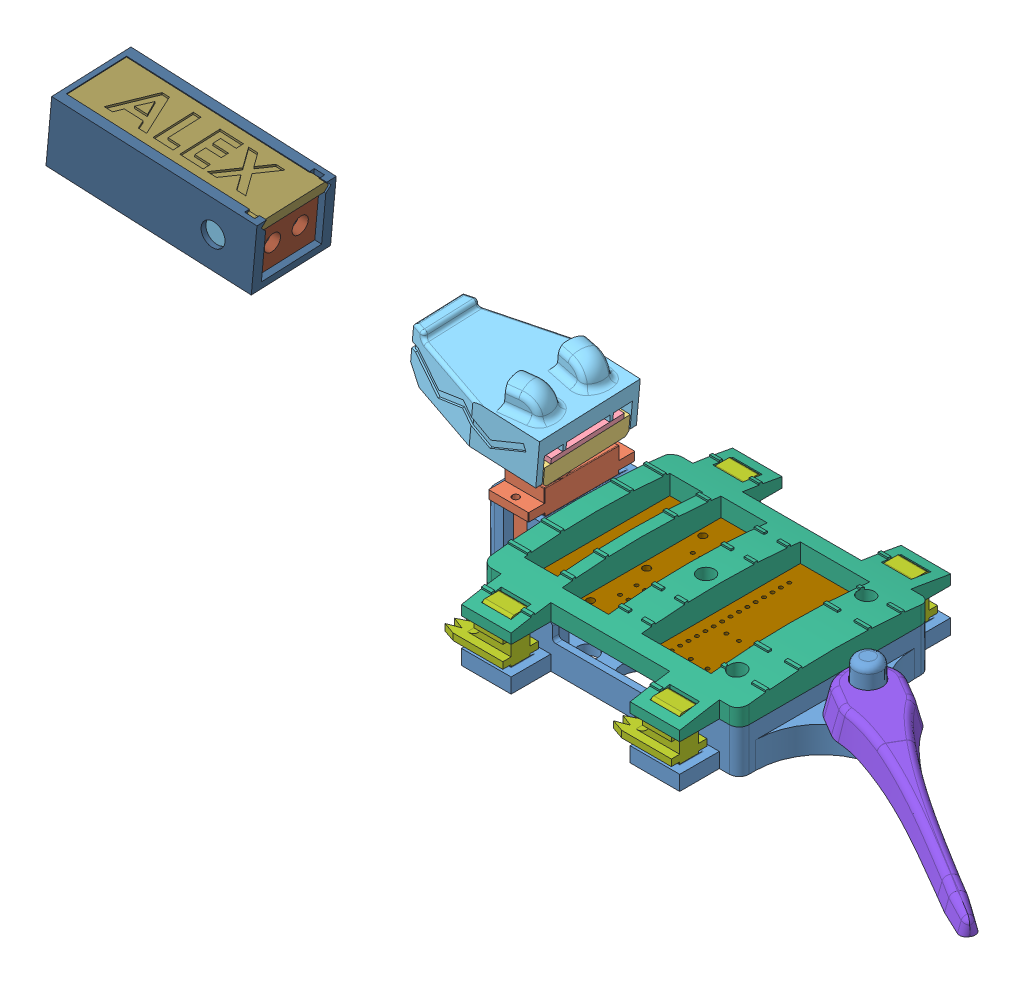
SolidWorks assembly Full Assem, configuration Default. Lengths in mm.
Overall size (309.58 66.54 94.12).
20 component instances, 14 part files, 33 mates.
Components (placement in the parent):
- Base-1: Base [Default] at origin size (113.5 23 82)
- SG90 SERVO-1: SG90 SERVO [Default] at (-49.45 1.1 -5.775) x (-1 0 0) z (0 1 0) size (12.35 32.2 30.15)
- GatorHead Assem-1: GatorHead Assem [Default] at (-51.3952 31.4702 -0.4724) x (0.039866 0 0.999205) z (-0.995403 0.087156 0.039714) size (31.75 20.5 44.45)
  - ServoHead-1: ServoHead [Default] at origin size (27 5.5 37.18)
  - SampleCircuitBoard-1: SampleCircuitBoard [Default] at (0 5.5 -3) size (23 1.5 22)
  - GatorHead-1: GatorHead [Default] at (0 1.3 8.225) size (31.75 19.2 44.45)
- GatorBody V2-1: GatorBody V2 [Default] at (0 13 0) size (78 7.26 82)
- GatorLegs-1: GatorLegs [Default] at (-21.25 8.75 34.875) x (0 1 0) z (0 0 1) size (16.5 18.75 10.75)
- GatorTail-1: GatorTail [Default] at (42.9693 9 -3.554) x (0.861525 0 0.507716) z (-0.507716 0 0.861525) size (94 9.48 21.08)
- GatorLegs-2: GatorLegs [Default] at (-21.25 8.75 -34.875) x (0 1 0) z (0 0 1) size (16.5 18.75 10.75)
- GatorLegs-3: GatorLegs [Default] at (29.75 8.75 34.875) x (0 1 0) z (0 0 1) size (16.5 18.75 10.75)
- GatorLegs-4: GatorLegs [Default] at (29.75 8.75 -34.875) x (0 1 0) z (0 0 1) size (16.5 18.75 10.75)
- SampleShield V2-1: SampleShield V2 [Default] at (0 11 0) size (70 1.5 50)
- FlashlightAssem-1: FlashlightAssem [Default] at (-149.8443 45 6.8332) x (0.995403 -0.087156 -0.039714) z (0.039866 0 0.999205) size (60 19 25)
  - FlashlightBase-1: FlashlightBase [Default] at origin size (60 19 25)
  - LEDInsert-1: LEDInsert [Default] at (25.25 8.875 0.125) x (0 -1 0) z (0 0 1) size (13.75 2.75 21.75)
  - FlashlightTop V2-1: FlashlightTop V2 [Default] at (0.5 16 0) size (58 2.75 21.75)
  - FlashlightConeInsert-1: FlashlightConeInsert [Default] at (-15 11 -6.875) x (-0.874067 0 -0.485806) z (-0.485806 0 0.874067) size (8 7.5 8) (hidden)
  - FlashlightConeInsert-2: FlashlightConeInsert [Default] at (0 11 4.875) x (-0.834603 0 -0.550852) z (-0.550852 0 0.834603) size (8 7.5 8)
  - SampleFlashlightPCB-1: SampleFlashlightPCB [Default] at (0.25 2 0) size (50 1.5 18)
Mates (geometry in assembly coordinates):
- Coincident1: coordinate: point of Base-1
- Coincident2: coincident anti-aligned: plane of Base-1 through (0 3 0) normal (0 1 0); plane of BreadBoard-1 through (-4.15 3 0) normal (0 -1 0)
- Coincident3: coincident anti-aligned: plane of Base-1 through (37 120.2008 0) normal (-1 0 0); plane of BreadBoard-1 through (37 11 -27) normal (1 0 0)
- Coincident4: coincident anti-aligned: plane of Base-1 through (0 120.2008 -27) normal (0 0 1); plane of BreadBoard-1 through (-45.3 11 -27) normal (0 0 -1)
- Concentric1: concentric anti-aligned: cylinder of SG90 SERVO-1 through (-49.45 29.6 -0.55) axis (0 1 0) radius 2.45; cylinder of GatorHead Assem-1/ServoHead-1 through (-49.45 34.25 -0.55) axis (0 -1 0) radius 3
- Coincident15: coincident aligned: plane of Base-1 through (0 0 0) normal (0 0 1); plane of GatorBody V2-1 through (0 13 0) normal (0 0 1)
- Coincident16: coincident aligned: plane of Base-1 through (0 0 0) normal (1 0 0); plane of GatorBody V2-1 through (0 13 0) normal (1 0 0)
- Coincident17: coincident anti-aligned: plane of Base-1 through (-30 4.5 0) normal (1 0 0); plane of GatorLegs-1 through (-30 8.75 34.875) normal (-1 0 0)
- Coincident18: coincident anti-aligned: plane of Base-1 through (0 4.5 32) normal (0 0 1); plane of GatorLegs-1 through (-30 8.75 32) normal (0 0 -1)
- Concentric2: concentric aligned: cylinder of Base-1 through (49 44.3137 0) axis (0 -1 0) radius 4; cylinder of GatorTail-1 through (49 69 0) axis (0 -1 0) radius 4.25
- Coincident22: coincident anti-aligned: plane of Base-1 through (21 4.5 0) normal (1 0 0); plane of GatorLegs-3 through (21 8.75 34.875) normal (-1 0 0)
- Coincident24: coincident anti-aligned: plane of Base-1 through (0 4.5 32) normal (0 0 1); plane of GatorLegs-3 through (21 8.75 32) normal (0 0 -1)
- Coincident26: coincident anti-aligned: plane of Base-1 through (0 4.5 -32) normal (0 0 -1); plane of GatorLegs-2 through (-30 8.75 -32) normal (0 0 1)
- Coincident27: coincident aligned: plane of GatorLegs-2 through (-30 8.75 -37.75) normal (0 0 -1); plane of GatorLegs-4 through (21 8.75 -37.75) normal (0 0 -1)
- Coincident28: coincident anti-aligned: plane of Base-1 through (-30 4.5 0) normal (1 0 0); plane of GatorLegs-2 through (-30 8.75 -34.875) normal (-1 0 0)
- Coincident29: coincident anti-aligned: plane of Base-1 through (21 4.5 0) normal (1 0 0); plane of GatorLegs-4 through (21 8.75 -34.875) normal (-1 0 0)
- Coincident31: coincident aligned: plane of GatorLegs-2 through (-30 17 -34.875) normal (0 1 0); plane of GatorLegs-4 through (21 17 -34.875) normal (0 1 0)
- Coincident32: coincident anti-aligned: plane of Base-1 through (0 17 0) normal (0 1 0); plane of SG90 SERVO-1 through (-49.45 17 -5.775) normal (0 -1 0)
- Coincident34: coincident anti-aligned: plane of Base-1 through (49 9 0) normal (0 1 0); plane of GatorTail-1 through (56.7537 9 4.5694) normal (0 -1 0)
- Distance1: distance = 3 mm anti-aligned: plane of SG90 SERVO-1 through (-49.45 31.25 -5.775) normal (0 1 0); plane of GatorHead Assem-1/ServoHead-1 through (-51.3952 34.25 -0.4724) normal (0 -1 0)
- Coincident36: coincident anti-aligned: plane of Base-1 through (0 4.5 0) normal (0 1 0); plane of GatorLegs-1 through (-30 4.5 34.875) normal (0 -1 0)
- Coincident37: coincident aligned: plane of GatorLegs-3 through (21 17 34.875) normal (0 1 0); plane of GatorLegs-4 through (21 17 -34.875) normal (0 1 0)
- Coincident38: coincident aligned: plane of GatorLegs-1 through (-30 17 34.875) normal (0 1 0); plane of GatorLegs-3 through (21 17 34.875) normal (0 1 0)
- Coincident39: coincident anti-aligned: plane of Base-1 through (0 66.9464 5.5) normal (0 0 -1); plane of SG90 SERVO-1 through (-43.4 1.1 5.5) normal (0 0 1)
- Coincident40: coincident anti-aligned: plane of Base-1 through (-55.5 66.9464 0) normal (1 0 0); plane of SG90 SERVO-1 through (-55.5 1.1 5.5) normal (-1 0 0)
- Coincident42: coincident aligned: plane of Base-1 through (0 0 0) normal (0 0 1); plane of SampleShield V2-1 through (0 11 0) normal (0 0 1)
- Coincident43: coincident aligned: plane of Base-1 through (0 0 0) normal (1 0 0); plane of SampleShield V2-1 through (0 11 0) normal (1 0 0)
- Coincident44: coincident anti-aligned: plane of GatorBody V2-1 through (0 13 0) normal (0 -1 0); plane of GatorLegs-1 through (-30 13 34.875) normal (0 1 0)
- Coincident45: coincident: unknown of FlashlightAssem-1
- Parallel1: parallel anti-aligned: plane of GatorHead Assem-1/GatorHead-1 through (-81.1188 48.0708 -15.1741) normal (-0.995403 0.087156 0.039714); plane of FlashlightAssem-1/FlashlightBase-1 through (-119.3097 44.3777 18.1248) normal (0.995403 -0.087156 -0.039714)
- Parallel2: parallel aligned: plane of GatorHead Assem-1/GatorHead-1 through (-79.8531 48.0708 16.5506) normal (0.039866 0 0.999205); plane of FlashlightAssem-1/FlashlightBase-1 through (-179.0339 49.6071 20.5077) normal (0.039866 0 0.999205)
- Coincident48: coincident aligned: plane of GatorHead Assem-1/GatorHead-1 through (-79.8531 48.0708 16.5506) normal (0.039866 0 0.999205); plane of FlashlightAssem-1/FlashlightBase-1 through (-179.0339 49.6071 20.5077) normal (0.039866 0 0.999205)
- Coincident50: coincident anti-aligned: plane of Base-1 through (0 11 0) normal (0 1 0); plane of SampleShield V2-1 through (0 11 0) normal (0 -1 0)
